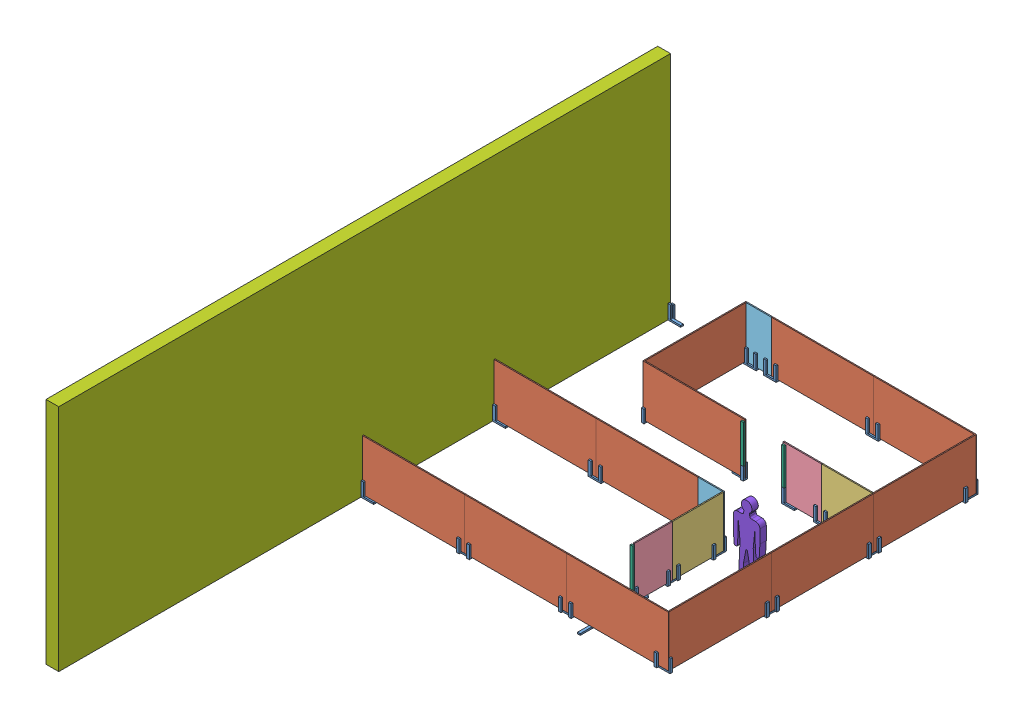
SolidWorks assembly MiniDemo, configuration Default. Lengths in mm.
Overall size (7658.1 5486.4 14668.5).
143 component instances, 8 part files, 135 mates.
Components (placement in the parent):
- EndBracket-1: EndBracket [Default] at (305.1343 92.5704 228.4122) size (304.8 342.9 101.6)
  - 2x3-1: 2x3 [Default] at (-333.5921 34.5788 116.8126) size (304.8 38.1 63.5)
  - 2x3-2: 2x3 [Default] at (-270.0921 -3.5212 53.3126) x (0 1 0) z (1 0 0) size (304.8 38.1 63.5)
  - 2x3-3: 2x3 [Default] at (-333.5921 339.3788 116.8126) x (0 -1 0) z (-1 0 0) size (304.8 38.1 63.5)
- Bracket-1: Bracket [Default] at (2397.744 104.1208 322.6145) size (304.8 342.9 101.6)
  - 2x3-1: 2x3 [Default] at (-140.2018 23.0285 22.6103) size (304.8 38.1 63.5)
  - 2x3-2: 2x3 [Default] at (164.5982 327.8285 -15.4897) x (0 -1 0) z (1 0 0) size (304.8 38.1 63.5)
  - 2x3-3: 2x3 [Default] at (-140.2018 327.8285 22.6103) x (0 -1 0) z (-1 0 0) size (304.8 38.1 63.5)
  - 2x3-4: 2x3 [Default] at (101.0982 289.7285 -40.8897) x (0 -1 0) z (-1 0 0) size (304.8 38.1 63.5)
  - 2x3-5: 2x3 [Default] at (-140.2018 289.7285 -40.8897) x (0 -1 0) z (-1 0 0) size (304.8 38.1 63.5)
- 4x8Foam-2: 4x8Foam [Default] at (2409.9422 1346.3492 281.7248) size (2438.4 1219.2 25.4)
- Bracket-2: Bracket [Default] at (4836.144 104.1208 322.6145) size (304.8 342.9 101.6)
  - 2x3-1: 2x3 [Default] at (-140.2018 23.0285 22.6103) size (304.8 38.1 63.5)
  - 2x3-2: 2x3 [Default] at (164.5982 327.8285 -15.4897) x (0 -1 0) z (1 0 0) size (304.8 38.1 63.5)
  - 2x3-3: 2x3 [Default] at (-140.2018 327.8285 22.6103) x (0 -1 0) z (-1 0 0) size (304.8 38.1 63.5)
  - 2x3-4: 2x3 [Default] at (101.0982 289.7285 -40.8897) x (0 -1 0) z (-1 0 0) size (304.8 38.1 63.5)
  - 2x3-5: 2x3 [Default] at (-140.2018 289.7285 -40.8897) x (0 -1 0) z (-1 0 0) size (304.8 38.1 63.5)
- 4x8Foam-3: 4x8Foam [Default] at (4848.3422 1346.3492 281.7248) size (2438.4 1219.2 25.4)
- Corner Bracket-1: Corner Bracket [Default] at (7268.5455 100.014 470.2188) x (0 0 1) z (-1 0 0) size (342.9 342.9 101.6)
  - 2x3-1: 2x3 [Default] at (-188.494 27.1353 45.3033) size (304.8 38.1 63.5)
  - 2x3-2: 2x3 [Default] at (-99.594 331.9353 7.2033) x (0 -1 0) z (1 0 0) size (304.8 38.1 63.5)
  - 2x3-3: 2x3 [Default] at (-188.494 293.8353 45.3033) x (0 -1 0) z (0 0 1) size (304.8 38.1 63.5)
  - 2x3-6: 2x3 [Default] at (52.806 331.9353 45.3033) x (0 -1 0) z (-1 0 0) size (304.8 38.1 63.5)
  - 2x3-7: 2x3 [Default] at (52.806 293.8353 -18.1967) x (0 -1 0) z (-1 0 0) size (304.8 38.1 63.5)
- 4x8Foam-4: 4x8Foam [Default] at (7286.7422 1346.3492 307.1248) x (0 0 1) z (-1 0 0) size (2438.4 1219.2 25.4)
- Bracket-3: Bracket [Default] at (7245.8525 104.1208 2733.3266) x (0 0 1) z (-1 0 0) size (304.8 342.9 101.6)
  - 2x3-1: 2x3 [Default] at (-140.2018 23.0285 22.6103) size (304.8 38.1 63.5)
  - 2x3-2: 2x3 [Default] at (164.5982 327.8285 -15.4897) x (0 -1 0) z (1 0 0) size (304.8 38.1 63.5)
  - 2x3-3: 2x3 [Default] at (-140.2018 327.8285 22.6103) x (0 -1 0) z (-1 0 0) size (304.8 38.1 63.5)
  - 2x3-4: 2x3 [Default] at (101.0982 289.7285 -40.8897) x (0 -1 0) z (-1 0 0) size (304.8 38.1 63.5)
  - 2x3-5: 2x3 [Default] at (-140.2018 289.7285 -40.8897) x (0 -1 0) z (-1 0 0) size (304.8 38.1 63.5)
- 4x8Foam-5: 4x8Foam [Default] at (7286.7422 1346.3492 2745.5248) x (0 0 1) z (-1 0 0) size (2438.4 1219.2 25.4)
- Bracket-4: Bracket [Default] at (7245.8525 104.1208 5171.7266) x (0 0 1) z (-1 0 0) size (304.8 342.9 101.6)
  - 2x3-1: 2x3 [Default] at (-140.2018 23.0285 22.6103) size (304.8 38.1 63.5)
  - 2x3-2: 2x3 [Default] at (164.5982 327.8285 -15.4897) x (0 -1 0) z (1 0 0) size (304.8 38.1 63.5)
  - 2x3-3: 2x3 [Default] at (-140.2018 327.8285 22.6103) x (0 -1 0) z (-1 0 0) size (304.8 38.1 63.5)
  - 2x3-4: 2x3 [Default] at (101.0982 289.7285 -40.8897) x (0 -1 0) z (-1 0 0) size (304.8 38.1 63.5)
  - 2x3-5: 2x3 [Default] at (-140.2018 289.7285 -40.8897) x (0 -1 0) z (-1 0 0) size (304.8 38.1 63.5)
- 4x8Foam-6: 4x8Foam [Default] at (7286.7422 1346.3492 5183.9248) x (0 0 1) z (-1 0 0) size (2438.4 1219.2 25.4)
- Corner Bracket-2: Corner Bracket [Default] at (7098.2482 100.014 7629.5281) x (-1 0 0) z (0 0 -1) size (342.9 342.9 101.6)
  - 2x3-1: 2x3 [Default] at (-188.494 27.1353 45.3033) size (304.8 38.1 63.5)
  - 2x3-2: 2x3 [Default] at (-99.594 331.9353 7.2033) x (0 -1 0) z (1 0 0) size (304.8 38.1 63.5)
  - 2x3-3: 2x3 [Default] at (-188.494 293.8353 45.3033) x (0 -1 0) z (0 0 1) size (304.8 38.1 63.5)
  - 2x3-6: 2x3 [Default] at (52.806 331.9353 45.3033) x (0 -1 0) z (-1 0 0) size (304.8 38.1 63.5)
  - 2x3-7: 2x3 [Default] at (52.806 293.8353 -18.1967) x (0 -1 0) z (-1 0 0) size (304.8 38.1 63.5)
- 4x8Foam-7: 4x8Foam [Default] at (4848.3422 1346.3492 7622.3248) size (2438.4 1219.2 25.4)
- Bracket-5: Bracket [Default] at (4860.5404 104.1208 7606.8351) x (-1 0 0) z (0 0 -1) size (304.8 342.9 101.6)
  - 2x3-1: 2x3 [Default] at (-140.2018 23.0285 22.6103) size (304.8 38.1 63.5)
  - 2x3-2: 2x3 [Default] at (164.5982 327.8285 -15.4897) x (0 -1 0) z (1 0 0) size (304.8 38.1 63.5)
  - 2x3-3: 2x3 [Default] at (-140.2018 327.8285 22.6103) x (0 -1 0) z (-1 0 0) size (304.8 38.1 63.5)
  - 2x3-4: 2x3 [Default] at (101.0982 289.7285 -40.8897) x (0 -1 0) z (-1 0 0) size (304.8 38.1 63.5)
  - 2x3-5: 2x3 [Default] at (-140.2018 289.7285 -40.8897) x (0 -1 0) z (-1 0 0) size (304.8 38.1 63.5)
- 4x8Foam-8: 4x8Foam [Default] at (2409.9422 1346.3492 7622.3248) size (2438.4 1219.2 25.4)
- Bracket-6: Bracket [Default] at (2422.1404 104.1208 7606.8351) x (-1 0 0) z (0 0 -1) size (304.8 342.9 101.6)
  - 2x3-1: 2x3 [Default] at (-140.2018 23.0285 22.6103) size (304.8 38.1 63.5)
  - 2x3-2: 2x3 [Default] at (164.5982 327.8285 -15.4897) x (0 -1 0) z (1 0 0) size (304.8 38.1 63.5)
  - 2x3-3: 2x3 [Default] at (-140.2018 327.8285 22.6103) x (0 -1 0) z (-1 0 0) size (304.8 38.1 63.5)
  - 2x3-4: 2x3 [Default] at (101.0982 289.7285 -40.8897) x (0 -1 0) z (-1 0 0) size (304.8 38.1 63.5)
  - 2x3-5: 2x3 [Default] at (-140.2018 289.7285 -40.8897) x (0 -1 0) z (-1 0 0) size (304.8 38.1 63.5)
- 4x8Foam-9: 4x8Foam [Default] at (-28.4578 1346.3492 7622.3248) size (2438.4 1219.2 25.4)
- EndBracket-2: EndBracket [Default] at (305.1343 92.5704 7569.0122) size (304.8 342.9 101.6)
  - 2x3-1: 2x3 [Default] at (-333.5921 34.5788 116.8126) size (304.8 38.1 63.5)
  - 2x3-2: 2x3 [Default] at (-270.0921 -3.5212 53.3126) x (0 1 0) z (1 0 0) size (304.8 38.1 63.5)
  - 2x3-3: 2x3 [Default] at (-333.5921 339.3788 116.8126) x (0 -1 0) z (-1 0 0) size (304.8 38.1 63.5)
- 4x8Foam-10: 4x8Foam [Default] at (1800.3422 1346.3492 281.7248) x (0 0 1) z (-1 0 0) size (2438.4 1219.2 25.4)
- Corner Bracket-3: Corner Bracket [Default] at (1793.1389 100.014 2557.0308) x (0 0 -1) z (1 0 0) size (342.9 342.9 101.6)
  - 2x3-1: 2x3 [Default] at (-188.494 27.1353 45.3033) size (304.8 38.1 63.5)
  - 2x3-2: 2x3 [Default] at (-99.594 331.9353 7.2033) x (0 -1 0) z (1 0 0) size (304.8 38.1 63.5)
  - 2x3-3: 2x3 [Default] at (-188.494 293.8353 45.3033) x (0 -1 0) z (0 0 1) size (304.8 38.1 63.5)
  - 2x3-6: 2x3 [Default] at (52.806 331.9353 45.3033) x (0 -1 0) z (-1 0 0) size (304.8 38.1 63.5)
  - 2x3-7: 2x3 [Default] at (52.806 293.8353 -18.1967) x (0 -1 0) z (-1 0 0) size (304.8 38.1 63.5)
- 4x8Foam-11: 4x8Foam [Default] at (1774.9422 1346.3492 2720.1248) size (2438.4 1219.2 25.4)
- EndBracket-4: EndBracket [Default] at (3879.7501 92.5704 2798.8373) x (-1 0 0) z (0 0 -1) size (304.8 342.9 101.6)
  - 2x3-1: 2x3 [Default] at (-333.5921 34.5788 116.8126) size (304.8 38.1 63.5)
  - 2x3-2: 2x3 [Default] at (-270.0921 -3.5212 53.3126) x (0 1 0) z (1 0 0) size (304.8 38.1 63.5)
  - 2x3-3: 2x3 [Default] at (-333.5921 339.3788 116.8126) x (0 -1 0) z (-1 0 0) size (304.8 38.1 63.5)
- 4x4Foam-1: 4x4Foam [Default] at (6042.1422 1346.3492 2720.1248) size (1219.2 1219.2 25.4)
- EndBracket-6: EndBracket [Default] at (6889.6501 92.5704 2798.8373) x (-1 0 0) z (0 0 -1) size (304.8 342.9 101.6)
  - 2x3-1: 2x3 [Default] at (-333.5921 34.5788 116.8126) size (304.8 38.1 63.5)
  - 2x3-2: 2x3 [Default] at (-270.0921 -3.5212 53.3126) x (0 1 0) z (1 0 0) size (304.8 38.1 63.5)
  - 2x3-3: 2x3 [Default] at (-333.5921 339.3788 116.8126) x (0 -1 0) z (-1 0 0) size (304.8 38.1 63.5)
- 4x1.5Foam-1: 4x1.5Foam [Default] at (5432.5422 1346.3492 6631.7248) x (0 0 -1) z (1 0 0) size (914.4 1219.2 25.4)
- EndBracket-7: EndBracket [Default] at (5379.2296 92.5704 6298.1327) x (0 0 -1) z (1 0 0) size (304.8 342.9 101.6)
  - 2x3-1: 2x3 [Default] at (-333.5921 34.5788 116.8126) size (304.8 38.1 63.5)
  - 2x3-2: 2x3 [Default] at (-270.0921 -3.5212 53.3126) x (0 1 0) z (1 0 0) size (304.8 38.1 63.5)
  - 2x3-3: 2x3 [Default] at (-333.5921 339.3788 116.8126) x (0 -1 0) z (-1 0 0) size (304.8 38.1 63.5)
- Bracket-8: Bracket [Default] at (5417.0525 104.1208 5705.1266) x (0 0 1) z (-1 0 0) size (304.8 342.9 101.6)
  - 2x3-1: 2x3 [Default] at (-140.2018 23.0285 22.6103) size (304.8 38.1 63.5)
  - 2x3-2: 2x3 [Default] at (164.5982 327.8285 -15.4897) x (0 -1 0) z (1 0 0) size (304.8 38.1 63.5)
  - 2x3-3: 2x3 [Default] at (-140.2018 327.8285 22.6103) x (0 -1 0) z (-1 0 0) size (304.8 38.1 63.5)
  - 2x3-4: 2x3 [Default] at (101.0982 289.7285 -40.8897) x (0 -1 0) z (-1 0 0) size (304.8 38.1 63.5)
  - 2x3-5: 2x3 [Default] at (-140.2018 289.7285 -40.8897) x (0 -1 0) z (-1 0 0) size (304.8 38.1 63.5)
- 4x4Foam-2: 4x4Foam [Default] at (5432.5422 1346.3492 5717.3248) x (0 0 -1) z (1 0 0) size (1219.2 1219.2 25.4)
- Corner Bracket-4: Corner Bracket [Default] at (5439.7455 100.014 4661.2188) x (0 0 1) z (-1 0 0) size (342.9 342.9 101.6)
  - 2x3-1: 2x3 [Default] at (-188.494 27.1353 45.3033) size (304.8 38.1 63.5)
  - 2x3-2: 2x3 [Default] at (-99.594 331.9353 7.2033) x (0 -1 0) z (1 0 0) size (304.8 38.1 63.5)
  - 2x3-3: 2x3 [Default] at (-188.494 293.8353 45.3033) x (0 -1 0) z (0 0 1) size (304.8 38.1 63.5)
  - 2x3-6: 2x3 [Default] at (52.806 331.9353 45.3033) x (0 -1 0) z (-1 0 0) size (304.8 38.1 63.5)
  - 2x3-7: 2x3 [Default] at (52.806 293.8353 -18.1967) x (0 -1 0) z (-1 0 0) size (304.8 38.1 63.5)
- 4x2Foam-1: 4x2Foam [Default] at (4848.3422 1346.3492 4472.7248) size (609.6 1219.2 25.4)
- Bracket-9: Bracket [Default] at (4836.144 104.1208 4513.6145) size (304.8 342.9 101.6)
  - 2x3-1: 2x3 [Default] at (-140.2018 23.0285 22.6103) size (304.8 38.1 63.5)
  - 2x3-2: 2x3 [Default] at (164.5982 327.8285 -15.4897) x (0 -1 0) z (1 0 0) size (304.8 38.1 63.5)
  - 2x3-3: 2x3 [Default] at (-140.2018 327.8285 22.6103) x (0 -1 0) z (-1 0 0) size (304.8 38.1 63.5)
  - 2x3-4: 2x3 [Default] at (101.0982 289.7285 -40.8897) x (0 -1 0) z (-1 0 0) size (304.8 38.1 63.5)
  - 2x3-5: 2x3 [Default] at (-140.2018 289.7285 -40.8897) x (0 -1 0) z (-1 0 0) size (304.8 38.1 63.5)
- 4x8Foam-12: 4x8Foam [Default] at (2409.9422 1346.3492 4472.7248) size (2438.4 1219.2 25.4)
- Bracket-10: Bracket [Default] at (2397.744 104.1208 4513.6145) size (304.8 342.9 101.6)
  - 2x3-1: 2x3 [Default] at (-140.2018 23.0285 22.6103) size (304.8 38.1 63.5)
  - 2x3-2: 2x3 [Default] at (164.5982 327.8285 -15.4897) x (0 -1 0) z (1 0 0) size (304.8 38.1 63.5)
  - 2x3-3: 2x3 [Default] at (-140.2018 327.8285 22.6103) x (0 -1 0) z (-1 0 0) size (304.8 38.1 63.5)
  - 2x3-4: 2x3 [Default] at (101.0982 289.7285 -40.8897) x (0 -1 0) z (-1 0 0) size (304.8 38.1 63.5)
  - 2x3-5: 2x3 [Default] at (-140.2018 289.7285 -40.8897) x (0 -1 0) z (-1 0 0) size (304.8 38.1 63.5)
- 4x8Foam-13: 4x8Foam [Default] at (-28.4578 1346.3492 4472.7248) size (2438.4 1219.2 25.4)
- EndBracket-8: EndBracket [Default] at (305.1343 92.5704 4419.4122) size (304.8 342.9 101.6)
  - 2x3-1: 2x3 [Default] at (-333.5921 34.5788 116.8126) size (304.8 38.1 63.5)
  - 2x3-2: 2x3 [Default] at (-270.0921 -3.5212 53.3126) x (0 1 0) z (1 0 0) size (304.8 38.1 63.5)
  - 2x3-3: 2x3 [Default] at (-333.5921 339.3788 116.8126) x (0 -1 0) z (-1 0 0) size (304.8 38.1 63.5)
- Bracket-11: Bracket [Default] at (6029.944 104.1208 2761.0145) size (304.8 342.9 101.6)
  - 2x3-1: 2x3 [Default] at (-140.2018 23.0285 22.6103) size (304.8 38.1 63.5)
  - 2x3-2: 2x3 [Default] at (164.5982 327.8285 -15.4897) x (0 -1 0) z (1 0 0) size (304.8 38.1 63.5)
  - 2x3-3: 2x3 [Default] at (-140.2018 327.8285 22.6103) x (0 -1 0) z (-1 0 0) size (304.8 38.1 63.5)
  - 2x3-4: 2x3 [Default] at (101.0982 289.7285 -40.8897) x (0 -1 0) z (-1 0 0) size (304.8 38.1 63.5)
  - 2x3-5: 2x3 [Default] at (-140.2018 289.7285 -40.8897) x (0 -1 0) z (-1 0 0) size (304.8 38.1 63.5)
- 4x1.5Foam-2: 4x1.5Foam [Default] at (5127.7422 1346.3492 2720.1248) size (914.4 1219.2 25.4)
- EndBracket-9: EndBracket [Default] at (5461.3343 92.5704 2666.8122) size (304.8 342.9 101.6)
  - 2x3-1: 2x3 [Default] at (-333.5921 34.5788 116.8126) size (304.8 38.1 63.5)
  - 2x3-2: 2x3 [Default] at (-270.0921 -3.5212 53.3126) x (0 1 0) z (1 0 0) size (304.8 38.1 63.5)
  - 2x3-3: 2x3 [Default] at (-333.5921 339.3788 116.8126) x (0 -1 0) z (-1 0 0) size (304.8 38.1 63.5)
- DoorFrame-3: DoorFrame [Default] at (5394.4422 89.0492 6631.7248) size (63.5 1219.2 38.1)
- 2x3-1: 2x3 [Default] at (5457.9422 127.1492 7927.1248) x (0 0 -1) z (1 0 0) size (304.8 38.1 63.5)
- DoorFrame-4: DoorFrame [Default] at (5394.4422 89.0492 7584.2248) size (63.5 1219.2 38.1)
- Wall-1: Wall [Default] at (-333.2578 5575.4492 281.7248) size (304.8 5486.4 14630.4)
- Human-1: Human [Default] at (6324.749 89.0492 4738.7665) size (660.4 1752.6 152.4)
- 4x2Foam-2: 4x2Foam [Default] at (1800.3422 1346.3492 281.7248) size (609.6 1219.2 25.4)
- Corner Bracket-5: Corner Bracket [Default] at (1963.4362 100.014 299.9215) size (342.9 342.9 101.6)
  - 2x3-1: 2x3 [Default] at (-188.494 27.1353 45.3033) size (304.8 38.1 63.5)
  - 2x3-2: 2x3 [Default] at (-99.594 331.9353 7.2033) x (0 -1 0) z (1 0 0) size (304.8 38.1 63.5)
  - 2x3-3: 2x3 [Default] at (-188.494 293.8353 45.3033) x (0 -1 0) z (0 0 1) size (304.8 38.1 63.5)
  - 2x3-6: 2x3 [Default] at (52.806 331.9353 45.3033) x (0 -1 0) z (-1 0 0) size (304.8 38.1 63.5)
  - 2x3-7: 2x3 [Default] at (52.806 293.8353 -18.1967) x (0 -1 0) z (-1 0 0) size (304.8 38.1 63.5)
- DoorFrame-5: DoorFrame [Default] at (4149.8422 89.0492 2745.5248) size (63.5 1219.2 38.1)
- DoorFrame-6: DoorFrame [Default] at (5127.7422 89.0492 2745.5248) size (63.5 1219.2 38.1)
Mates (geometry in assembly coordinates):
- Coincident4: coincident aligned: plane of EndBracket-1/2x3-1 through (276.3422 89.0492 345.2248) normal (0 -1 0); plane of Bracket-1/2x3-1 through (2562.3422 89.0492 345.2248) normal (0 -1 0)
- Coincident6: coincident aligned: plane of EndBracket-1/2x3-3 through (-28.4578 127.1492 345.2248) normal (0 0 1); plane of Bracket-1/2x3-3 through (2257.5422 127.1492 345.2248) normal (0 0 1)
- Coincident11: coincident aligned: plane of Bracket-1/2x3-1 through (2562.3422 89.0492 345.2248) normal (0 -1 0); plane of Bracket-2/2x3-1 through (5000.7422 89.0492 345.2248) normal (0 -1 0)
- Coincident12: coincident aligned: plane of Bracket-1/2x3-2 through (2562.3422 127.1492 345.2248) normal (0 0 1); plane of Bracket-2/2x3-3 through (4695.9422 127.1492 345.2248) normal (0 0 1)
- Distance2: distance = 152.4 mm aligned: plane of 4x8Foam-2 through (4848.3422 1346.3492 307.1248) normal (1 0 0); plane of Bracket-2/2x3-1 through (5000.7422 127.1492 345.2248) normal (1 0 0)
- Coincident14: coincident aligned: plane of 4x8Foam-2 through (2409.9422 1346.3492 307.1248) normal (0 0 1); plane of 4x8Foam-3 through (4848.3422 1346.3492 307.1248) normal (0 0 1)
- Coincident15: coincident aligned: plane of 4x8Foam-2 through (2409.9422 1346.3492 307.1248) normal (0 1 0); plane of 4x8Foam-3 through (4848.3422 1346.3492 307.1248) normal (0 1 0)
- Coincident16: coincident anti-aligned: plane of 4x8Foam-2 through (4848.3422 1346.3492 307.1248) normal (1 0 0); plane of 4x8Foam-3 through (4848.3422 1346.3492 307.1248) normal (-1 0 0)
- Coincident17: coincident anti-aligned: plane of 4x8Foam-3 through (4848.3422 1346.3492 281.7248) normal (0 0 -1); plane of Corner Bracket-1/2x3-3 through (7223.2422 89.0492 281.7248) normal (0 0 1)
- Coincident18: coincident aligned: plane of 4x8Foam-3 through (7286.7422 1346.3492 307.1248) normal (1 0 0); plane of Corner Bracket-1/2x3-1 through (7286.7422 127.1492 586.5248) normal (1 0 0)
- Coincident19: coincident anti-aligned: plane of 4x8Foam-3 through (4848.3422 127.1492 307.1248) normal (0 -1 0); plane of Corner Bracket-1/2x3-1 through (7223.2422 127.1492 586.5248) normal (0 1 0)
- Coincident20: coincident aligned: plane of 4x8Foam-3 through (4848.3422 1346.3492 307.1248) normal (0 1 0); plane of 4x8Foam-4 through (7261.3422 1346.3492 307.1248) normal (0 1 0)
- Coincident21: coincident anti-aligned: plane of 4x8Foam-3 through (4848.3422 1346.3492 307.1248) normal (0 0 1); plane of 4x8Foam-4 through (7261.3422 1346.3492 307.1248) normal (0 0 -1)
- Coincident22: coincident aligned: plane of 4x8Foam-3 through (7286.7422 1346.3492 307.1248) normal (1 0 0); plane of 4x8Foam-4 through (7286.7422 1346.3492 307.1248) normal (1 0 0)
- Coincident23: coincident anti-aligned: plane of 4x8Foam-4 through (7286.7422 1346.3492 307.1248) normal (1 0 0); plane of Bracket-3/2x3-4 through (7286.7422 89.0492 2834.4248) normal (-1 0 0)
- Coincident24: coincident anti-aligned: plane of 4x8Foam-4 through (7261.3422 127.1492 307.1248) normal (0 -1 0); plane of Bracket-3/2x3-1 through (7223.2422 127.1492 2897.9248) normal (0 1 0)
- Distance3: distance = 152.4 mm aligned: plane of 4x8Foam-4 through (7261.3422 1346.3492 2745.5248) normal (0 0 1); plane of Bracket-3/2x3-1 through (7223.2422 127.1492 2897.9248) normal (0 0 1)
- Coincident26: coincident aligned: plane of 4x8Foam-4 through (7261.3422 1346.3492 307.1248) normal (0 1 0); plane of 4x8Foam-5 through (7261.3422 1346.3492 2745.5248) normal (0 1 0)
- Coincident27: coincident anti-aligned: plane of 4x8Foam-4 through (7261.3422 1346.3492 2745.5248) normal (0 0 1); plane of 4x8Foam-5 through (7261.3422 1346.3492 2745.5248) normal (0 0 -1)
- Coincident28: coincident aligned: plane of 4x8Foam-4 through (7261.3422 1346.3492 307.1248) normal (-1 0 0); plane of 4x8Foam-5 through (7261.3422 1346.3492 2745.5248) normal (-1 0 0)
- Coincident29: coincident aligned: plane of Bracket-3/2x3-4 through (7286.7422 393.8492 2834.4248) normal (0 1 0); plane of Bracket-4/2x3-4 through (7286.7422 393.8492 5272.8248) normal (0 1 0)
- Coincident30: coincident aligned: plane of Bracket-3/2x3-4 through (7324.8422 89.0492 2834.4248) normal (1 0 0); plane of Bracket-4/2x3-4 through (7324.8422 89.0492 5272.8248) normal (1 0 0)
- Distance4: distance = 152.4 mm aligned: plane of Bracket-4/2x3-1 through (7223.2422 127.1492 5336.3248) normal (0 0 1); plane of 4x8Foam-5 through (7261.3422 1346.3492 5183.9248) normal (0 0 1)
- Coincident32: coincident aligned: plane of 4x8Foam-5 through (7261.3422 1346.3492 2745.5248) normal (0 1 0); plane of 4x8Foam-6 through (7261.3422 1346.3492 5183.9248) normal (0 1 0)
- Coincident33: coincident anti-aligned: plane of 4x8Foam-5 through (7261.3422 1346.3492 5183.9248) normal (0 0 1); plane of 4x8Foam-6 through (7261.3422 1346.3492 5183.9248) normal (0 0 -1)
- Coincident34: coincident aligned: plane of 4x8Foam-5 through (7261.3422 1346.3492 2745.5248) normal (-1 0 0); plane of 4x8Foam-6 through (7261.3422 1346.3492 5183.9248) normal (-1 0 0)
- Coincident35: coincident anti-aligned: plane of 4x8Foam-6 through (7286.7422 1346.3492 5183.9248) normal (1 0 0); plane of Corner Bracket-2/2x3-3 through (7286.7422 89.0492 7584.2248) normal (-1 0 0)
- Coincident37: coincident anti-aligned: plane of 4x8Foam-6 through (7261.3422 127.1492 5183.9248) normal (0 -1 0); plane of Corner Bracket-2/2x3-1 through (6981.9422 127.1492 7584.2248) normal (0 1 0)
- Coincident38: coincident aligned: plane of 4x8Foam-6 through (7261.3422 1346.3492 5183.9248) normal (0 1 0); plane of 4x8Foam-7 through (4848.3422 1346.3492 7647.7248) normal (0 1 0)
- Coincident41: coincident anti-aligned: plane of 4x8Foam-7 through (4848.3422 1346.3492 7647.7248) normal (0 0 1); plane of Bracket-5/2x3-5 through (5000.7422 89.0492 7647.7248) normal (0 0 -1)
- Coincident42: coincident aligned: plane of Corner Bracket-2/2x3-7 through (7045.4422 393.8492 7647.7248) normal (0 1 0); plane of Bracket-5/2x3-5 through (5000.7422 393.8492 7647.7248) normal (0 1 0)
- Distance5: distance = 152.4 mm aligned: plane of 4x8Foam-7 through (4848.3422 1346.3492 7647.7248) normal (-1 0 0); plane of Bracket-5/2x3-1 through (4695.9422 127.1492 7584.2248) normal (-1 0 0)
- Coincident44: coincident aligned: plane of 4x8Foam-7 through (4848.3422 1346.3492 7647.7248) normal (0 0 1); plane of 4x8Foam-8 through (2409.9422 1346.3492 7647.7248) normal (0 0 1)
- Coincident45: coincident aligned: plane of 4x8Foam-7 through (4848.3422 1346.3492 7647.7248) normal (0 1 0); plane of 4x8Foam-8 through (2409.9422 1346.3492 7647.7248) normal (0 1 0)
- Coincident46: coincident anti-aligned: plane of 4x8Foam-7 through (4848.3422 1346.3492 7647.7248) normal (-1 0 0); plane of 4x8Foam-8 through (4848.3422 1346.3492 7647.7248) normal (1 0 0)
- Coincident47: coincident anti-aligned: plane of 4x8Foam-8 through (2409.9422 1346.3492 7647.7248) normal (0 0 1); plane of Bracket-6/2x3-4 through (2321.0422 89.0492 7647.7248) normal (0 0 -1)
- Coincident48: coincident aligned: plane of Bracket-5/2x3-4 through (4759.4422 393.8492 7647.7248) normal (0 1 0); plane of Bracket-6/2x3-4 through (2321.0422 393.8492 7647.7248) normal (0 1 0)
- Distance6: distance = 152.4 mm aligned: plane of 4x8Foam-8 through (2409.9422 1346.3492 7647.7248) normal (-1 0 0); plane of Bracket-6/2x3-1 through (2257.5422 127.1492 7584.2248) normal (-1 0 0)
- Coincident50: coincident aligned: plane of 4x8Foam-8 through (2409.9422 1346.3492 7647.7248) normal (0 1 0); plane of 4x8Foam-9 through (-28.4578 1346.3492 7647.7248) normal (0 1 0)
- Coincident51: coincident aligned: plane of 4x8Foam-8 through (2409.9422 1346.3492 7647.7248) normal (0 0 1); plane of 4x8Foam-9 through (-28.4578 1346.3492 7647.7248) normal (0 0 1)
- Coincident52: coincident anti-aligned: plane of 4x8Foam-8 through (2409.9422 1346.3492 7647.7248) normal (-1 0 0); plane of 4x8Foam-9 through (2409.9422 1346.3492 7647.7248) normal (1 0 0)
- Coincident53: coincident anti-aligned: plane of 4x8Foam-9 through (-28.4578 1346.3492 7647.7248) normal (0 0 1); plane of EndBracket-2/2x3-3 through (-28.4578 127.1492 7647.7248) normal (0 0 -1)
- Coincident54: coincident aligned: plane of 4x8Foam-9 through (-28.4578 1346.3492 7647.7248) normal (-1 0 0); plane of EndBracket-2/2x3-3 through (-28.4578 127.1492 7685.8248) normal (-1 0 0)
- Coincident55: coincident anti-aligned: plane of 4x8Foam-9 through (-28.4578 127.1492 7647.7248) normal (0 -1 0); plane of EndBracket-2/2x3-1 through (276.3422 127.1492 7685.8248) normal (0 1 0)
- Coincident65: coincident anti-aligned: plane of 4x8Foam-10 through (1774.9422 1346.3492 281.7248) normal (-1 0 0); plane of Corner Bracket-3/2x3-7 through (1774.9422 89.0492 2504.2248) normal (1 0 0)
- Coincident66: coincident anti-aligned: plane of 4x8Foam-10 through (1774.9422 127.1492 281.7248) normal (0 -1 0); plane of Corner Bracket-3/2x3-1 through (1838.4422 127.1492 2440.7248) normal (0 1 0)
- Coincident67: coincident aligned: plane of 4x8Foam-10 through (1774.9422 1346.3492 2720.1248) normal (0 0 1); plane of Corner Bracket-3/2x3-2 through (1800.3422 127.1492 2720.1248) normal (0 0 1)
- Coincident68: coincident aligned: plane of 4x8Foam-10 through (1774.9422 1346.3492 281.7248) normal (-1 0 0); plane of 4x8Foam-11 through (1774.9422 1346.3492 2745.5248) normal (-1 0 0)
- Coincident69: coincident aligned: plane of 4x8Foam-10 through (1774.9422 1346.3492 281.7248) normal (0 1 0); plane of 4x8Foam-11 through (1774.9422 1346.3492 2745.5248) normal (0 1 0)
- Coincident70: coincident anti-aligned: plane of 4x8Foam-10 through (1774.9422 1346.3492 2720.1248) normal (0 0 1); plane of 4x8Foam-11 through (1774.9422 1346.3492 2720.1248) normal (0 0 -1)
- Coincident71: coincident anti-aligned: plane of 4x8Foam-11 through (1774.9422 1346.3492 2745.5248) normal (0 0 1); plane of EndBracket-4/2x3-2 through (4149.8422 393.8492 2745.5248) normal (0 0 -1)
- Coincident72: coincident aligned: plane of 4x8Foam-11 through (4213.3422 1346.3492 2745.5248) normal (1 0 0); plane of EndBracket-4/2x3-2 through (4213.3422 393.8492 2745.5248) normal (1 0 0)
- Coincident73: coincident anti-aligned: plane of 4x8Foam-11 through (1774.9422 127.1492 2745.5248) normal (0 -1 0); plane of EndBracket-4/2x3-1 through (3908.5422 127.1492 2682.0248) normal (0 1 0)
- Coincident77: coincident aligned: plane of 4x8Foam-5 through (7261.3422 1346.3492 2745.5248) normal (0 1 0); plane of 4x4Foam-1 through (6042.1422 1346.3492 2745.5248) normal (0 1 0)
- Coincident80: coincident anti-aligned: plane of Bracket-3/2x3-1 through (7223.2422 127.1492 2897.9248) normal (-1 0 0); plane of EndBracket-6/2x3-1 through (7223.2422 127.1492 2682.0248) normal (1 0 0)
- Coincident81: coincident aligned: plane of Bracket-3/2x3-3 through (7223.2422 431.9492 2593.1248) normal (0 1 0); plane of EndBracket-6/2x3-3 through (7223.2422 431.9492 2682.0248) normal (0 1 0)
- Coincident82: coincident anti-aligned: plane of 4x4Foam-1 through (6042.1422 1346.3492 2745.5248) normal (0 0 1); plane of EndBracket-6/2x3-2 through (7159.7422 393.8492 2745.5248) normal (0 0 -1)
- Coincident84: coincident aligned: plane of 4x8Foam-7 through (4848.3422 1346.3492 7647.7248) normal (0 1 0); plane of 4x1.5Foam-1 through (5457.9422 1346.3492 6631.7248) normal (0 1 0)
- Coincident86: coincident anti-aligned: plane of 4x1.5Foam-1 through (5432.5422 1346.3492 6631.7248) normal (-1 0 0); plane of EndBracket-7/2x3-2 through (5432.5422 393.8492 6568.2248) normal (1 0 0)
- Coincident87: coincident aligned: plane of 4x1.5Foam-1 through (5457.9422 1346.3492 6631.7248) normal (0 0 1); plane of EndBracket-7/2x3-1 through (5496.0422 127.1492 6631.7248) normal (0 0 1)
- Coincident88: coincident anti-aligned: plane of 4x1.5Foam-1 through (5457.9422 127.1492 6631.7248) normal (0 -1 0); plane of EndBracket-7/2x3-1 through (5496.0422 127.1492 6326.9248) normal (0 1 0)
- Coincident89: coincident aligned: plane of EndBracket-7/2x3-3 through (5496.0422 431.9492 6631.7248) normal (0 1 0); plane of Bracket-8/2x3-2 through (5432.5422 431.9492 5869.7248) normal (0 1 0)
- Coincident90: coincident anti-aligned: plane of 4x1.5Foam-1 through (5457.9422 1346.3492 6631.7248) normal (1 0 0); plane of Bracket-8/2x3-4 through (5457.9422 89.0492 5806.2248) normal (-1 0 0)
- Distance12: distance = 152.4 mm aligned: plane of Bracket-8/2x3-1 through (5394.4422 127.1492 5564.9248) normal (0 0 -1); plane of 4x1.5Foam-1 through (5457.9422 1346.3492 5717.3248) normal (0 0 -1)
- Coincident92: coincident aligned: plane of 4x1.5Foam-1 through (5457.9422 1346.3492 6631.7248) normal (0 1 0); plane of 4x4Foam-2 through (5457.9422 1346.3492 5717.3248) normal (0 1 0)
- Coincident93: coincident aligned: plane of 4x1.5Foam-1 through (5457.9422 1346.3492 6631.7248) normal (1 0 0); plane of 4x4Foam-2 through (5457.9422 1346.3492 5717.3248) normal (1 0 0)
- Coincident94: coincident anti-aligned: plane of 4x1.5Foam-1 through (5457.9422 1346.3492 5717.3248) normal (0 0 -1); plane of 4x4Foam-2 through (5457.9422 1346.3492 5717.3248) normal (0 0 1)
- Coincident95: coincident anti-aligned: plane of 4x4Foam-2 through (5457.9422 1346.3492 5717.3248) normal (1 0 0); plane of Corner Bracket-4/2x3-7 through (5457.9422 89.0492 4714.0248) normal (-1 0 0)
- Coincident96: coincident aligned: plane of 4x4Foam-2 through (5457.9422 1346.3492 4498.1248) normal (0 0 -1); plane of Corner Bracket-4/2x3-2 through (5432.5422 127.1492 4498.1248) normal (0 0 -1)
- Coincident97: coincident anti-aligned: plane of 4x4Foam-2 through (5457.9422 127.1492 5717.3248) normal (0 -1 0); plane of Corner Bracket-4/2x3-1 through (5394.4422 127.1492 4777.5248) normal (0 1 0)
- Coincident98: coincident aligned: plane of 4x4Foam-2 through (5457.9422 1346.3492 5717.3248) normal (1 0 0); plane of 4x2Foam-1 through (5457.9422 1346.3492 4498.1248) normal (1 0 0)
- Coincident99: coincident anti-aligned: plane of 4x4Foam-2 through (5457.9422 1346.3492 4498.1248) normal (0 0 -1); plane of 4x2Foam-1 through (4848.3422 1346.3492 4498.1248) normal (0 0 1)
- Coincident100: coincident aligned: plane of 4x4Foam-2 through (5457.9422 1346.3492 5717.3248) normal (0 1 0); plane of 4x2Foam-1 through (4848.3422 1346.3492 4498.1248) normal (0 1 0)
- Coincident101: coincident aligned: plane of Corner Bracket-4/2x3-3 through (5394.4422 393.8492 4472.7248) normal (0 1 0); plane of Bracket-9/2x3-4 through (4937.2422 393.8492 4472.7248) normal (0 1 0)
- Coincident102: coincident aligned: plane of Corner Bracket-4/2x3-3 through (5394.4422 89.0492 4434.6248) normal (0 0 -1); plane of Bracket-9/2x3-4 through (4937.2422 89.0492 4434.6248) normal (0 0 -1)
- Distance13: distance = 152.4 mm aligned: plane of Bracket-9/2x3-3 through (4695.9422 127.1492 4536.2248) normal (-1 0 0); plane of 4x2Foam-1 through (4848.3422 1346.3492 4498.1248) normal (-1 0 0)
- Coincident104: coincident aligned: plane of 4x2Foam-1 through (4848.3422 1346.3492 4498.1248) normal (0 1 0); plane of 4x8Foam-12 through (2409.9422 1346.3492 4498.1248) normal (0 1 0)
- Coincident105: coincident aligned: plane of 4x2Foam-1 through (4848.3422 1346.3492 4472.7248) normal (0 0 -1); plane of 4x8Foam-12 through (2409.9422 1346.3492 4472.7248) normal (0 0 -1)
- Coincident106: coincident anti-aligned: plane of 4x2Foam-1 through (4848.3422 1346.3492 4498.1248) normal (-1 0 0); plane of 4x8Foam-12 through (4848.3422 1346.3492 4498.1248) normal (1 0 0)
- Coincident107: coincident aligned: plane of Bracket-9/2x3-5 through (4695.9422 393.8492 4472.7248) normal (0 1 0); plane of Bracket-10/2x3-4 through (2498.8422 393.8492 4472.7248) normal (0 1 0)
- Coincident108: coincident aligned: plane of Bracket-9/2x3-5 through (4695.9422 89.0492 4434.6248) normal (0 0 -1); plane of Bracket-10/2x3-4 through (2498.8422 89.0492 4434.6248) normal (0 0 -1)
- Distance14: distance = 152.4 mm aligned: plane of 4x8Foam-12 through (2409.9422 1346.3492 4498.1248) normal (-1 0 0); plane of Bracket-10/2x3-5 through (2257.5422 89.0492 4472.7248) normal (-1 0 0)
- Coincident110: coincident aligned: plane of 4x8Foam-12 through (2409.9422 1346.3492 4472.7248) normal (0 0 -1); plane of 4x8Foam-13 through (-28.4578 1346.3492 4472.7248) normal (0 0 -1)
- Coincident111: coincident aligned: plane of 4x8Foam-12 through (2409.9422 1346.3492 4498.1248) normal (0 1 0); plane of 4x8Foam-13 through (-28.4578 1346.3492 4498.1248) normal (0 1 0)
- Coincident112: coincident anti-aligned: plane of 4x8Foam-12 through (2409.9422 1346.3492 4498.1248) normal (-1 0 0); plane of 4x8Foam-13 through (2409.9422 1346.3492 4498.1248) normal (1 0 0)
- Coincident113: coincident aligned: plane of 4x8Foam-13 through (-28.4578 1346.3492 4498.1248) normal (-1 0 0); plane of EndBracket-8/2x3-2 through (-28.4578 393.8492 4472.7248) normal (-1 0 0)
- Coincident114: coincident anti-aligned: plane of 4x8Foam-13 through (-28.4578 1346.3492 4498.1248) normal (0 0 1); plane of EndBracket-8/2x3-3 through (-28.4578 127.1492 4498.1248) normal (0 0 -1)
- Coincident115: coincident anti-aligned: plane of 4x8Foam-13 through (-28.4578 127.1492 4498.1248) normal (0 -1 0); plane of EndBracket-8/2x3-1 through (276.3422 127.1492 4536.2248) normal (0 1 0)
- Coincident116: coincident aligned: plane of 4x8Foam-11 through (1774.9422 1346.3492 2745.5248) normal (0 0 1); plane of 4x4Foam-1 through (6042.1422 1346.3492 2745.5248) normal (0 0 1)
- Distance15: distance = 152.4 mm aligned: plane of 4x4Foam-1 through (6042.1422 1346.3492 2745.5248) normal (-1 0 0); plane of Bracket-11/2x3-1 through (5889.7422 127.1492 2783.6248) normal (-1 0 0)
- Coincident119: coincident anti-aligned: plane of 4x4Foam-1 through (6042.1422 1346.3492 2720.1248) normal (0 0 -1); plane of Bracket-11/2x3-4 through (6131.0422 89.0492 2720.1248) normal (0 0 1)
- Coincident120: coincident aligned: plane of Bracket-3/2x3-3 through (7223.2422 431.9492 2593.1248) normal (0 1 0); plane of Bracket-11/2x3-3 through (5889.7422 431.9492 2783.6248) normal (0 1 0)
- Coincident121: coincident aligned: plane of 4x4Foam-1 through (6042.1422 1346.3492 2745.5248) normal (0 1 0); plane of 4x1.5Foam-2 through (5127.7422 1346.3492 2745.5248) normal (0 1 0)
- Coincident122: coincident aligned: plane of 4x4Foam-1 through (6042.1422 1346.3492 2720.1248) normal (0 0 -1); plane of 4x1.5Foam-2 through (5127.7422 1346.3492 2720.1248) normal (0 0 -1)
- Coincident123: coincident anti-aligned: plane of 4x4Foam-1 through (6042.1422 1346.3492 2745.5248) normal (-1 0 0); plane of 4x1.5Foam-2 through (6042.1422 1346.3492 2745.5248) normal (1 0 0)
- Coincident124: coincident aligned: plane of Bracket-11/2x3-1 through (6194.5422 127.1492 2783.6248) normal (0 1 0); plane of EndBracket-9/2x3-1 through (5432.5422 127.1492 2783.6248) normal (0 1 0)
- Coincident125: coincident aligned: plane of Bracket-11/2x3-3 through (5889.7422 127.1492 2783.6248) normal (0 0 1); plane of EndBracket-9/2x3-3 through (5127.7422 127.1492 2783.6248) normal (0 0 1)
- Coincident126: coincident aligned: plane of 4x1.5Foam-2 through (5127.7422 1346.3492 2745.5248) normal (-1 0 0); plane of EndBracket-9/2x3-2 through (5127.7422 393.8492 2720.1248) normal (-1 0 0)
- Coincident135: coincident aligned: plane of 4x1.5Foam-1 through (5457.9422 1346.3492 6631.7248) normal (1 0 0); plane of DoorFrame-3 through (5457.9422 1308.2492 6631.7248) normal (1 0 0)
- Coincident136: coincident aligned: plane of EndBracket-7/2x3-1 through (5496.0422 89.0492 6326.9248) normal (0 -1 0); plane of DoorFrame-3 through (5394.4422 89.0492 6631.7248) normal (0 -1 0)
- Coincident137: coincident anti-aligned: plane of EndBracket-7/2x3-2 through (5432.5422 393.8492 6631.7248) normal (0 0 1); plane of DoorFrame-3 through (5394.4422 1308.2492 6631.7248) normal (0 0 -1)
- Coincident138: coincident aligned: plane of 4x8Foam-7 through (4848.3422 1346.3492 7622.3248) normal (0 0 -1); plane of 2x3-1 through (5457.9422 127.1492 7622.3248) normal (0 0 -1)
- Coincident139: coincident aligned: plane of EndBracket-7/2x3-1 through (5496.0422 127.1492 6326.9248) normal (0 1 0); plane of 2x3-1 through (5457.9422 127.1492 7622.3248) normal (0 1 0)
- Coincident140: coincident aligned: plane of DoorFrame-3 through (5457.9422 1308.2492 6631.7248) normal (1 0 0); plane of 2x3-1 through (5457.9422 127.1492 7622.3248) normal (1 0 0)
- Coincident141: coincident aligned: plane of DoorFrame-3 through (5457.9422 1308.2492 6631.7248) normal (1 0 0); plane of DoorFrame-4 through (5457.9422 1308.2492 7584.2248) normal (1 0 0)
- Coincident142: coincident aligned: plane of DoorFrame-3 through (5394.4422 1308.2492 6631.7248) normal (0 1 0); plane of DoorFrame-4 through (5394.4422 1308.2492 7584.2248) normal (0 1 0)
- Coincident143: coincident anti-aligned: plane of 4x8Foam-7 through (4848.3422 1346.3492 7622.3248) normal (0 0 -1); plane of DoorFrame-4 through (5394.4422 1308.2492 7622.3248) normal (0 0 1)
- Distance17: distance = 914.4 mm anti-aligned: plane of DoorFrame-3 through (5394.4422 1308.2492 6669.8248) normal (0 0 1); plane of DoorFrame-4 through (5394.4422 1308.2492 7584.2248) normal (0 0 -1)
- Coincident146: coincident aligned: plane of EndBracket-1/2x3-1 through (276.3422 89.0492 345.2248) normal (0 -1 0); plane of Wall-1 through (-28.4578 89.0492 281.7248) normal (0 -1 0)
- Coincident148: coincident aligned: plane of 4x8Foam-6 through (7261.3422 1346.3492 7622.3248) normal (0 0 1); plane of Corner Bracket-2/2x3-2 through (7197.8422 127.1492 7622.3248) normal (0 0 1)
- Coincident149: coincident anti-aligned: plane of Corner Bracket-2/2x3-3 through (7286.7422 89.0492 7584.2248) normal (-1 0 0); plane of 4x8Foam-7 through (7286.7422 1346.3492 7647.7248) normal (1 0 0)
- Coincident150: coincident anti-aligned: plane of 4x8Foam-6 through (7261.3422 1346.3492 7622.3248) normal (0 0 1); plane of 4x8Foam-7 through (4848.3422 1346.3492 7622.3248) normal (0 0 -1)
- Coincident151: coincident anti-aligned: plane of EndBracket-8/2x3-2 through (-28.4578 393.8492 4472.7248) normal (-1 0 0); plane of Wall-1 through (-28.4578 5575.4492 281.7248) normal (1 0 0)
- Coincident152: coincident aligned: plane of Bracket-3/2x3-1 through (7223.2422 89.0492 2897.9248) normal (0 -1 0); plane of Human-1 through (6324.749 89.0492 4891.1665) normal (0 -1 0)
- Parallel1: parallel aligned: plane of 4x4Foam-1 through (6042.1422 1346.3492 2745.5248) normal (0 0 1); plane of Human-1 through (6324.749 89.0492 4891.1665) normal (0 0 1)
- Coincident154: coincident aligned: plane of 4x8Foam-2 through (2409.9422 1346.3492 307.1248) normal (0 0 1); plane of 4x2Foam-2 through (1800.3422 1346.3492 307.1248) normal (0 0 1)
- Coincident155: coincident aligned: plane of 4x8Foam-2 through (2409.9422 1346.3492 307.1248) normal (0 1 0); plane of 4x2Foam-2 through (1800.3422 1346.3492 307.1248) normal (0 1 0)
- Coincident156: coincident anti-aligned: plane of 4x8Foam-2 through (2409.9422 1346.3492 307.1248) normal (-1 0 0); plane of 4x2Foam-2 through (2409.9422 1346.3492 307.1248) normal (1 0 0)
- Coincident157: coincident anti-aligned: plane of EndBracket-1/2x3-1 through (276.3422 127.1492 345.2248) normal (0 1 0); plane of 4x2Foam-2 through (1800.3422 127.1492 307.1248) normal (0 -1 0)
- Coincident158: coincident anti-aligned: plane of Bracket-1/2x3-3 through (2257.5422 127.1492 307.1248) normal (0 0 -1); plane of 4x2Foam-2 through (1800.3422 1346.3492 307.1248) normal (0 0 1)
- Coincident159: coincident anti-aligned: plane of EndBracket-2/2x3-3 through (-28.4578 127.1492 7685.8248) normal (-1 0 0); plane of Wall-1 through (-28.4578 5575.4492 281.7248) normal (1 0 0)
- Coincident160: coincident anti-aligned: plane of EndBracket-1/2x3-2 through (-28.4578 393.8492 281.7248) normal (-1 0 0); plane of Wall-1 through (-28.4578 5575.4492 281.7248) normal (1 0 0)
- Coincident161: coincident aligned: plane of Bracket-1/2x3-3 through (2257.5422 127.1492 345.2248) normal (0 0 1); plane of Corner Bracket-5/2x3-6 through (2016.2422 127.1492 345.2248) normal (0 0 1)
- Coincident162: coincident aligned: plane of Bracket-1/2x3-3 through (2257.5422 431.9492 345.2248) normal (0 1 0); plane of Corner Bracket-5/2x3-6 through (2016.2422 431.9492 345.2248) normal (0 1 0)
- Coincident163: coincident aligned: plane of 4x2Foam-2 through (1800.3422 1346.3492 307.1248) normal (-1 0 0); plane of Corner Bracket-5/2x3-2 through (1800.3422 127.1492 307.1248) normal (-1 0 0)
- Coincident166: coincident aligned: plane of 4x8Foam-10 through (1774.9422 1346.3492 281.7248) normal (0 1 0); plane of 4x2Foam-2 through (1800.3422 1346.3492 307.1248) normal (0 1 0)
- Coincident168: coincident aligned: plane of 4x8Foam-10 through (1774.9422 1346.3492 281.7248) normal (0 0 -1); plane of 4x2Foam-2 through (1800.3422 1346.3492 281.7248) normal (0 0 -1)
- Coincident169: coincident anti-aligned: plane of 4x8Foam-4 through (7261.3422 1346.3492 307.1248) normal (-1 0 0); plane of 4x4Foam-1 through (7261.3422 1346.3492 2745.5248) normal (1 0 0)
- Coincident170: coincident anti-aligned: plane of 4x8Foam-10 through (1800.3422 1346.3492 281.7248) normal (1 0 0); plane of Corner Bracket-5/2x3-2 through (1800.3422 127.1492 307.1248) normal (-1 0 0)
- Coincident171: coincident: plane of EndBracket-4/2x3-2 through (4213.3422 393.8492 2745.5248) normal (1 0 0); plane of DoorFrame-5 through (4213.3422 1308.2492 2745.5248) normal (1 0 0)
- Coincident172: coincident: plane of EndBracket-4/2x3-2 through (4149.8422 393.8492 2783.6248) normal (0 0 1); plane of DoorFrame-5 through (4149.8422 1308.2492 2783.6248) normal (0 0 1)
- Coincident173: coincident aligned: plane of EndBracket-4/2x3-2 through (4149.8422 89.0492 2745.5248) normal (0 -1 0); plane of DoorFrame-5 through (4149.8422 89.0492 2745.5248) normal (0 -1 0)
- Coincident174: coincident: plane of EndBracket-9/2x3-1 through (5432.5422 89.0492 2783.6248) normal (0 -1 0); plane of DoorFrame-6 through (5127.7422 89.0492 2745.5248) normal (0 -1 0)
- Coincident175: coincident: plane of EndBracket-9/2x3-3 through (5191.2422 127.1492 2783.6248) normal (1 0 0); plane of DoorFrame-6 through (5191.2422 1308.2492 2745.5248) normal (1 0 0)
- Coincident176: coincident aligned: plane of EndBracket-9/2x3-3 through (5127.7422 127.1492 2783.6248) normal (0 0 1); plane of DoorFrame-6 through (5127.7422 1308.2492 2783.6248) normal (0 0 1)
